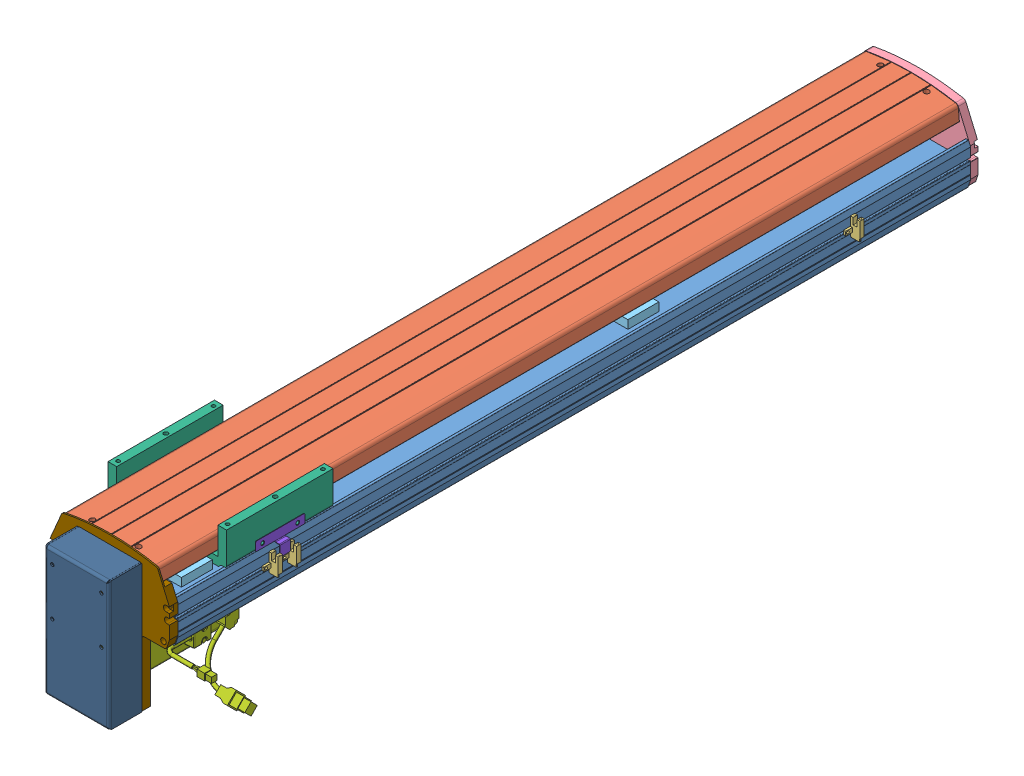
SolidWorks assembly S17M-BM-400W, configuration 默认. Lengths in mm.
Overall size (202.37 218.79 1201.01).
13 component instances, 10 part files, 40 mates.
Components (placement in the parent):
- T17-R-011底座^S17M-BM-400W-1: T17-R-011底座^S17M-BM-400W [默认] at origin size (170 60 1131) (virtual)
- T17S-L-007上盖^S17M-BM-400W-2: T17S-L-007上盖^S17M-BM-400W [Default] at (0 82 570.5) size (137.82 27.5 1141) (virtual)
- 672 传感器^S17M-BM-400W-1: 672 传感器^S17M-BM-400W [默认] at (91.7485 42.15 975.1) x (1 0 0) z (0 0 -1) size (13.5 27.4 26.1) (virtual)
- 672 传感器^S17M-BM-400W-2: 672 传感器^S17M-BM-400W [默认] at (91.7485 42.15 1001.2) x (1 0 0) z (0 0 -1) size (13.5 27.4 26.1) (virtual)
- 672 传感器^S17M-BM-400W-3: 672 传感器^S17M-BM-400W [默认] at (91.7485 42.15 171.65) x (1 0 0) z (0 0 -1) size (13.5 27.4 26.1) (virtual)
- T17S-L-001侧面板^S17M-BM-400W-1: T17S-L-001侧面板^S17M-BM-400W [默认] at (0 1 -11) size (169 101.5 11) (virtual)
- 滑座S17M^S17M-BM-400W-1: 滑座S17M^S17M-BM-400W [默认] at (0 75.7 432) x (-1 0 0) z (0 1 0) size (144.4 44 43.7) (virtual)
- 滑台S17M^S17M-BM-400W-1: 滑台S17M^S17M-BM-400W [默认] at (0 75.7 909) x (-1 0 0) z (0 1 0) size (169.2 152 78.7) (virtual)
- 滑座S17M^S17M-BM-400W-3: 滑座S17M^S17M-BM-400W [默认] at (0 75.7 1069) x (-1 0 0) z (0 1 0) size (144.4 44 43.7) (virtual)
- 400W电机ECMA-C20604RS^S17M-BM-400W-1: 400W电机ECMA-C20604RS^S17M-BM-400W [Default] at (0.0015 -45.05 1083.65) x (0 1 0) z (1 0 0) size (94.25 160.75 147.38) (virtual)
-  外置感应片ST14-17^S17M-BM-400W-2:  外置感应片ST14-17^S17M-BM-400W [默认] at (85.2 62.2 985) x (0 0 -1) z (1 0 0) size (70 30 7.6) (virtual)
- 电机板S17M-BM-60^S17M-BM-400W-1: 电机板S17M-BM-60^S17M-BM-400W [默认] at (-36.7012 39.9909 1131) size (170 196.1 12) (virtual)
- 复件 铝合金罩壳S17-BM^S17M-BM-400W-1: 复件 铝合金罩壳S17-BM^S17M-BM-400W [Default] at (0 -1.5 1188) x (0 1 0) z (0 0 -1) size (184.28 92.01 47.01) (virtual)
Mates (geometry in assembly coordinates):
- 重合148: coincident: plane of T17-R-011底座^S17M-BM-400W-1 through (0 0 0) normal (0 0 -1); plane of T17S-L-007上盖^S17M-BM-400W-2 through (66.7465 75.75 0) normal (0 0 -1)
- 重合153: coincident: plane of T17-R-011底座^S17M-BM-400W-1 through (0 0 0) normal (1 0 0); plane of T17S-L-007上盖^S17M-BM-400W-2 through (0 82 570.5) normal (1 0 0)
- 重合157: coincident: plane of 672 传感器^S17M-BM-400W-1 through (84.9985 53.25 968.8) normal (-1 0 0); plane of 672 传感器^S17M-BM-400W-3 through (84.9985 53.25 165.35) normal (-1 0 0)
- 重合159: coincident: plane of 672 传感器^S17M-BM-400W-1 through (84.9985 53.25 968.8) normal (0 1 0); plane of 672 传感器^S17M-BM-400W-3 through (84.9985 53.25 165.35) normal (0 1 0)
- 重合160: coincident: plane of 672 传感器^S17M-BM-400W-1 through (84.9985 53.25 968.8) normal (0 1 0); plane of 672 传感器^S17M-BM-400W-2 through (84.9985 53.25 994.9) normal (0 1 0)
- 距离20: distance = 31.55 mm: plane of T17-R-011底座^S17M-BM-400W-1 through (0 -0.5 1131) normal (0 -1 0); plane of 672 传感器^S17M-BM-400W-2 through (84.9985 31.05 994.9) normal (0 -1 0)
- 距离21: distance = 165.35 mm: plane of 672 传感器^S17M-BM-400W-3 through (98.4985 31.05 165.35) normal (0 0 -1); plane of T17-R-011底座^S17M-BM-400W-1 through (0 0 0) normal (0 0 -1)
- 重合168: coincident: plane of T17-R-011底座^S17M-BM-400W-1 through (84.9985 0 1131) normal (1 0 0); plane of 672 传感器^S17M-BM-400W-2 through (84.9985 53.25 994.9) normal (-1 0 0)
- 重合174: coincident: plane of T17-R-011底座^S17M-BM-400W-1 through (0 0 0) normal (0 0 -1); plane of T17S-L-001侧面板^S17M-BM-400W-1 through (0.0037 -247.5005 0) normal (0 0 1)
- 重合183: coincident: plane of T17-R-011底座^S17M-BM-400W-1 through (0 0 0) normal (1 0 0); plane of T17S-L-001侧面板^S17M-BM-400W-1 through (0 1 -11) normal (1 0 0)
- 距离23: distance = 82.5 mm: plane of T17S-L-007上盖^S17M-BM-400W-2 through (0 82 570.5) normal (0 1 0); plane of T17-R-011底座^S17M-BM-400W-1 through (0 -0.5 1131) normal (0 -1 0)
- 距离26: distance = 1 mm: plane of T17-R-011底座^S17M-BM-400W-1 through (0 0 0) normal (0 1 0); plane of T17S-L-001侧面板^S17M-BM-400W-1 through (0 1 -11) normal (0 1 0)
- 重合211: coordinate: point of T17-R-011底座^S17M-BM-400W-1; point of assembly
- 距离27: distance = 110 mm: plane of 滑台S17M^S17M-BM-400W-1 through (-113.7999 109.5 909) normal (0 1 0); plane of T17-R-011底座^S17M-BM-400W-1 through (0 -0.5 1131) normal (0 -1 0)
- 宽度1: width: plane of 滑台S17M^S17M-BM-400W-1 through (-84.6 65.3 1061) normal (-1 0 0); plane of 滑台S17M^S17M-BM-400W-1 through (84.6 111.2 1061) normal (1 0 0); plane of T17-R-011底座^S17M-BM-400W-1 through (84.4985 0 1131) normal (1 0 0); plane of T17-R-011底座^S17M-BM-400W-1 through (-84.4985 0 1131) normal (-1 0 0)
- 宽度2: width: plane of 滑台S17M^S17M-BM-400W-1 through (-84.6 65.3 1061) normal (-1 0 0); plane of 滑台S17M^S17M-BM-400W-1 through (84.6 111.2 1061) normal (1 0 0); plane of 滑座S17M^S17M-BM-400W-1 through (72.2 32 476) normal (1 0 0); plane of 滑座S17M^S17M-BM-400W-1 through (-72.2 32 476) normal (-1 0 0)
- 距离29: distance = 5 mm: plane of 滑座S17M^S17M-BM-400W-1 through (40 70.7 476) normal (0 1 0); plane of 滑台S17M^S17M-BM-400W-1 through (-40 75.7 1061) normal (0 1 0)
- 重合221: coincident: plane of 滑座S17M^S17M-BM-400W-1 through (-40 75.7 476) normal (0 1 0); plane of 滑座S17M^S17M-BM-400W-3 through (-40 75.7 1113) normal (0 1 0)
- 重合222: coincident: plane of 滑座S17M^S17M-BM-400W-1 through (-72.2 32 476) normal (-1 0 0); plane of 滑座S17M^S17M-BM-400W-3 through (-72.2 32 1113) normal (-1 0 0)
- 距离30: distance = 8 mm: plane of 滑座S17M^S17M-BM-400W-3 through (81.6 65.3 1069) normal (0 0 -1); plane of 滑台S17M^S17M-BM-400W-1 through (81.6 65.3 1061) normal (0 0 1)
- 距离31: distance: plane of 滑座S17M^S17M-BM-400W-3 through (81.6 65.3 1069) normal (0 0 -1); plane of 滑座S17M^S17M-BM-400W-1 through (81.6 65.3 476) normal (0 0 1)
- 重合233: coincident: plane of T17-R-011底座^S17M-BM-400W-1 through (84.9985 0 1131) normal (1 0 0); plane of 672 传感器^S17M-BM-400W-1 through (84.9985 53.25 968.8) normal (-1 0 0)
- 重合234: coincident: plane of 672 传感器^S17M-BM-400W-1 through (87.9985 34.25 985) normal (0 0 1); plane of 672 传感器^S17M-BM-400W-2 through (87.9985 34.25 985) normal (0 0 -1)
- 重合235: coincident: plane of 滑台S17M^S17M-BM-400W-1 through (84.6 111.2 1061) normal (1 0 0); plane of  外置感应片ST14-17^S17M-BM-400W-2 through (84.6 62.2 985) normal (-1 0 0)
- 同心1: concentric: cylinder of 滑台S17M^S17M-BM-400W-1 through (84.6 68.2 960) axis (1 0 0) radius 2.1; cylinder of  外置感应片ST14-17^S17M-BM-400W-2 through (85.2 68.2 960) axis (1 0 0) radius 2.75
- 同心2: concentric: cylinder of 滑台S17M^S17M-BM-400W-1 through (84.6 68.2 1010) axis (1 0 0) radius 2.1; circle of  外置感应片ST14-17^S17M-BM-400W-2
- LimitDistance1: limit distance = 7.5 mm: line of 672 传感器^S17M-BM-400W-1 through (87.9985 35.25 985) axis (0 1 0); plane of  外置感应片ST14-17^S17M-BM-400W-2 through (91.1 60.6 977.5) normal (0 0 -1)
- 重合236: coincident: plane of T17-R-011底座^S17M-BM-400W-1 through (0 0 1131) normal (0 0 1); plane of 电机板S17M-BM-60^S17M-BM-400W-1 through (-77.6083 5 1131) normal (0 0 -1)
- 重合238: coincident: plane of T17-R-011底座^S17M-BM-400W-1 through (-84.9985 0 1131) normal (-1 0 0); plane of 电机板S17M-BM-60^S17M-BM-400W-1 through (-84.9985 55.8992 1143) normal (-1 0 0)
- 距离32: distance = 1.5 mm: plane of 电机板S17M-BM-60^S17M-BM-400W-1 through (-77.6083 1 1143) normal (0 -1 0); plane of T17-R-011底座^S17M-BM-400W-1 through (0 -0.5 1131) normal (0 -1 0)
- 重合240: coincident: plane of 电机板S17M-BM-60^S17M-BM-400W-1 through (-77.6083 5 1143) normal (0 0 1); plane of 复件 铝合金罩壳S17-BM^S17M-BM-400W-1 through (46 90.5 1143) normal (0 0 -1)
- 重合241: coincident: plane of 复件 铝合金罩壳S17-BM^S17M-BM-400W-1 through (0 -1.5 1188) normal (1 0 0); plane of assembly through (0 0 0) normal (1 0 0)
- 重合242: coincident: plane of 电机板S17M-BM-60^S17M-BM-400W-1 through (-36.7012 -93.5 1131) normal (0 -1 0); plane of 复件 铝合金罩壳S17-BM^S17M-BM-400W-1 through (0 -93.5 1188) normal (0 -1 0)
- 相切1: tangent: cylinder of 400W电机ECMA-C20604RS^S17M-BM-400W-1 through (0.0015 -45.05 1131) axis (0 0 1) radius 25; plane of 电机板S17M-BM-60^S17M-BM-400W-1 through (-24.9985 -42.05 1131) normal (1 0 0)
- 重合243: coincident: plane of 400W电机ECMA-C20604RS^S17M-BM-400W-1 through (31.0472 -76.0957 1131) normal (0 0 1); plane of 电机板S17M-BM-60^S17M-BM-400W-1 through (-77.6083 5 1131) normal (0 0 -1)
- 平行1: parallel: line of 400W电机ECMA-C20604RS^S17M-BM-400W-1 through (-24.9985 -74.9016 1131) axis (1 0 0); plane of 电机板S17M-BM-60^S17M-BM-400W-1 through (-36.7012 -93.5 1131) normal (0 -1 0)
- 距离33: distance = 18.5 mm: line of 400W电机ECMA-C20604RS^S17M-BM-400W-1 through (-24.9985 -74.9016 1131) axis (1 0 0); plane of 电机板S17M-BM-60^S17M-BM-400W-1 through (-36.7012 -93.5 1131) normal (0 -1 0)
- 距离34: distance = 214 mm: line of 672 传感器^S17M-BM-400W-1 through (87.9985 35.25 985) axis (0 1 0); plane of 复件 铝合金罩壳S17-BM^S17M-BM-400W-1 through (0 3.5 1190) normal (0 0 1)
- 距离35: distance = 44.55 mm: plane of T17-R-011底座^S17M-BM-400W-1 through (0 -0.5 1131) normal (0 -1 0); cylinder of 400W电机ECMA-C20604RS^S17M-BM-400W-1 through (0.0015 -45.05 1160) axis (0 0 -1) radius 7
- 距离36: distance = 205 mm: plane of 复件 铝合金罩壳S17-BM^S17M-BM-400W-1 through (0 -1.5 1190) normal (0 0 1); cylinder of 滑台S17M^S17M-BM-400W-1 through (78 111.2 985) axis (0 1 0) radius 3
